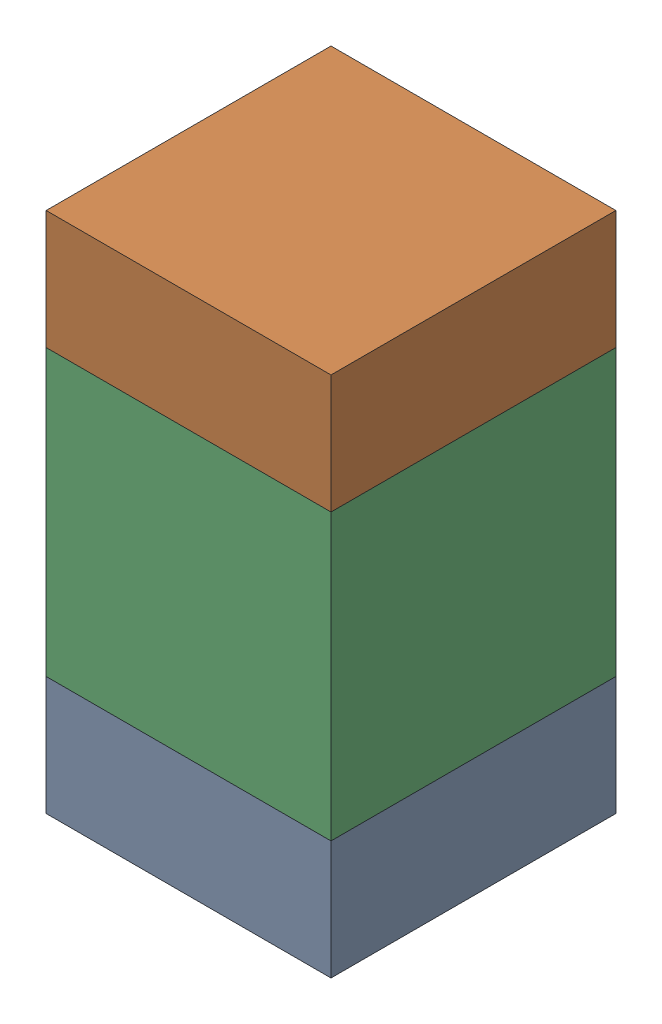
SolidWorks assembly C102_1PCB, configuration Default. Lengths in mm.
Overall size (0.6 1.1 0.6).
6 component instances, 2 part files, 0 mates.
Components (placement in the parent):
- 854785296-1: 854785296 [Default] at (110.1 120.875 0) size (0.6 0.25 0.6)
  - Extruded_10-1: Extruded_10 [Default] at origin size (0.6 0.25 0.6)
- 854785296-2: 854785296 [Default] at (110.1 121.725 0) size (0.6 0.25 0.6)
  - Extruded_10-1: Extruded_10 [Default] at origin size (0.6 0.25 0.6)
- 761606048-1: 761606048 [Default] at (110.1 121.3 0) size (0.6 0.6 0.6)
  - Extruded_9-1: Extruded_9 [Default] at origin size (0.6 0.6 0.6)
